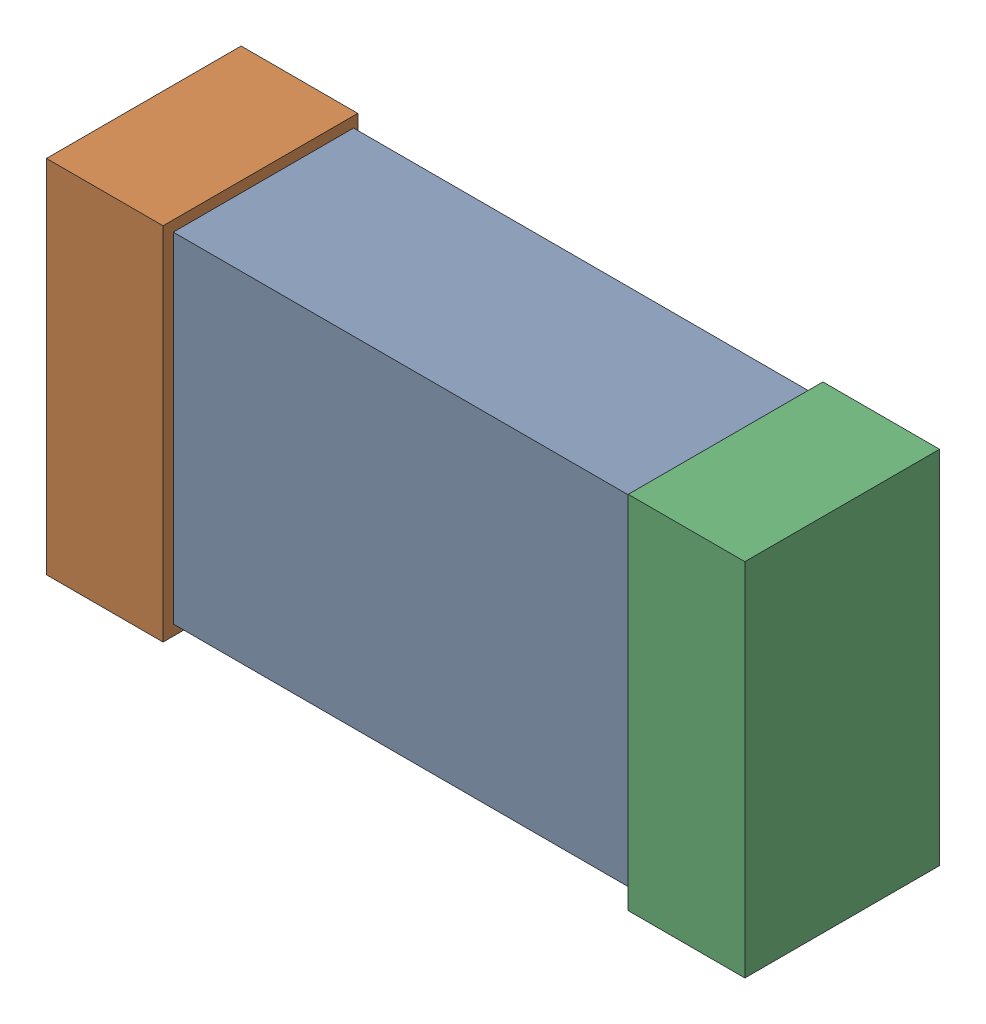
SolidWorks assembly R36, configuration Default. Lengths in mm.
Overall size (1.65 0.85 0.46).
6 component instances, 2 part files, 0 mates.
Components (placement in the parent):
- 432120720_1-1: 432120720_1 [Default] at (7.4501 34.9999 -0.8615) size (1.5 0.8 0.42)
  - Extruded (12)-1: Extruded (12) [Default] at origin size (1.5 0.8 0.42)
- 432120464_2-1: 432120464_2 [Default] at (6.7643 34.9999 -0.8715) size (0.28 0.85 0.46)
  - Extruded (11)-1: Extruded (11) [Default] at origin size (0.28 0.85 0.46)
- 432120464_3-1: 432120464_3 [Default] at (8.1358 34.9999 -0.8715) size (0.28 0.85 0.46)
  - Extruded (11)-1: Extruded (11) [Default] at origin size (0.28 0.85 0.46)
